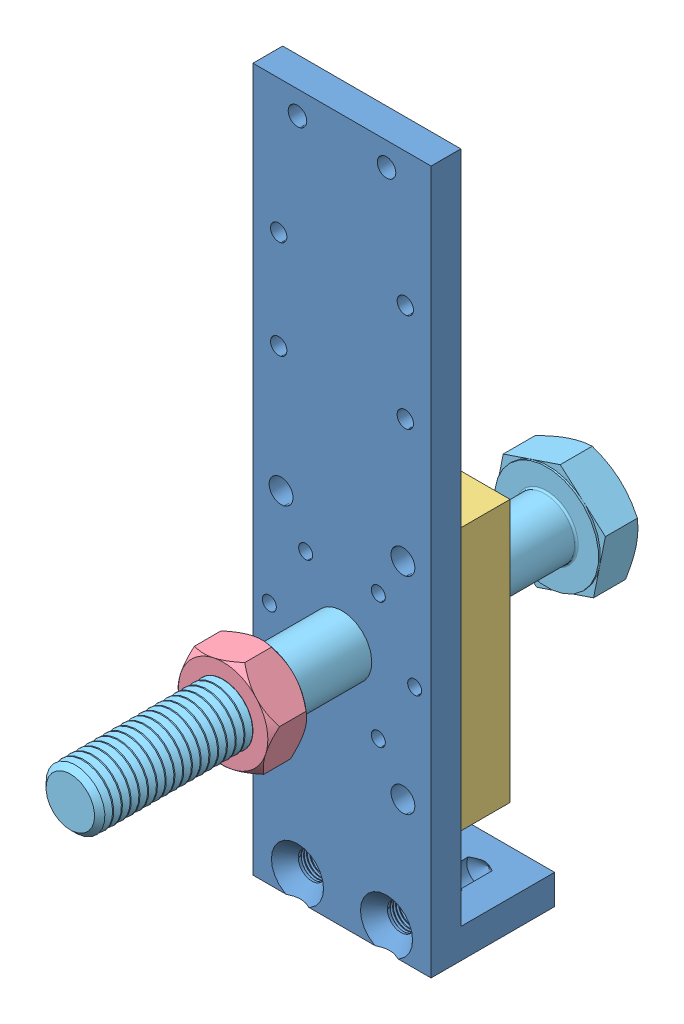
SolidWorks assembly Soporte Principal Del Chasis, configuration Predeterminado. Lengths in mm.
Overall size (71.11 203.98 109.8).
5 component instances, 5 part files, 7 mates.
Components (placement in the parent):
- soporte Llantas-1: soporte Llantas [Predeterminado] at (-199.0451 0.5704 44.994) size (71.11 203.98 26.35)
- instrument ball bearing_ai-1: instrument ball bearing_ai [Rodamiento Rodillo Llanta] at (-199.0451 -22.4296 36.994) x (0 0 -1) z (1 0 0) size (6.35 28.57 28.57)
- SOPORTE BALINERA-1: SOPORTE BALINERA [Predeterminado] at (-199.0451 -22.4296 33.819) size (38 56 10.5)
- hex jam nut_ai-1: hex jam nut_ai [HJNUT 0.5000-13-D-S] at (-199.0451 -22.4296 73.5162) x (0.739057 0.673642 0) z (0 0 1) size (19.05 22 8.2)
- heavy hex finished bolt_ai-1: heavy hex finished bolt_ai [Tornilleria LLantas] at (-199.0451 -22.4296 -3.681) x (0 0 1) z (0.319798 -0.947486 0) size (109.8 25.66 22.23)
Mates (geometry in assembly coordinates):
- Concéntrica2: concentric aligned: cylinder of Rodamiento Rodillo Llanta-1 through (-199.0451 -22.4296 57.6315) axis (0 0 -1) radius 14.2875; cylinder of SOPORTE BALINERA-1 through (-199.0451 -22.4296 41.819) axis (0 0 -1) radius 14.2875
- Coincidente1: coincident anti-aligned: plane of Rodamiento Rodillo Llanta-1 through (-199.0451 -8.5485 33.819) normal (0 0 -1); plane of SOPORTE BALINERA-1 through (-199.0451 -22.4296 33.819) normal (0 0 1)
- Concéntrica3: concentric anti-aligned: cylinder of soporte Llantas-1 through (-199.0451 -22.4296 22.769) axis (0 0 1) radius 6.35; cylinder of SOPORTE BALINERA-1 through (-199.0451 -22.4296 41.819) axis (0 0 -1) radius 14.2875
- Coincidente2: coincident anti-aligned: plane of soporte Llantas-1 through (-199.0451 0.5704 41.819) normal (0 0 -1); plane of SOPORTE BALINERA-1 through (-199.0451 -22.4296 41.819) normal (0 0 1)
- Concéntrica6: concentric aligned: cylinder of soporte Llantas-1 through (-186.0451 -0.4296 31.319) axis (0 0 -1) radius 2.5527; cylinder of SOPORTE BALINERA-1 through (-186.0451 -0.4296 31.319) axis (0 0 -1) radius 2.5527
- Concéntrica7: concentric aligned: cylinder of instrument ball bearing_ai-1 through (-199.0451 -22.4296 57.6315) axis (0 0 -1) radius 6.35; cylinder of heavy hex finished bolt_ai-1 through (-199.0451 -22.4296 -3.681) axis (0 0 -1) radius 6.35
- Distancia1: distance = 35 mm aligned: plane of heavy hex finished bolt_ai-1 through (-211.2028 -26.5331 -3.681) normal (0 0 -1); plane of SOPORTE BALINERA-1 through (-199.0451 -22.4296 31.319) normal (0 0 -1)
